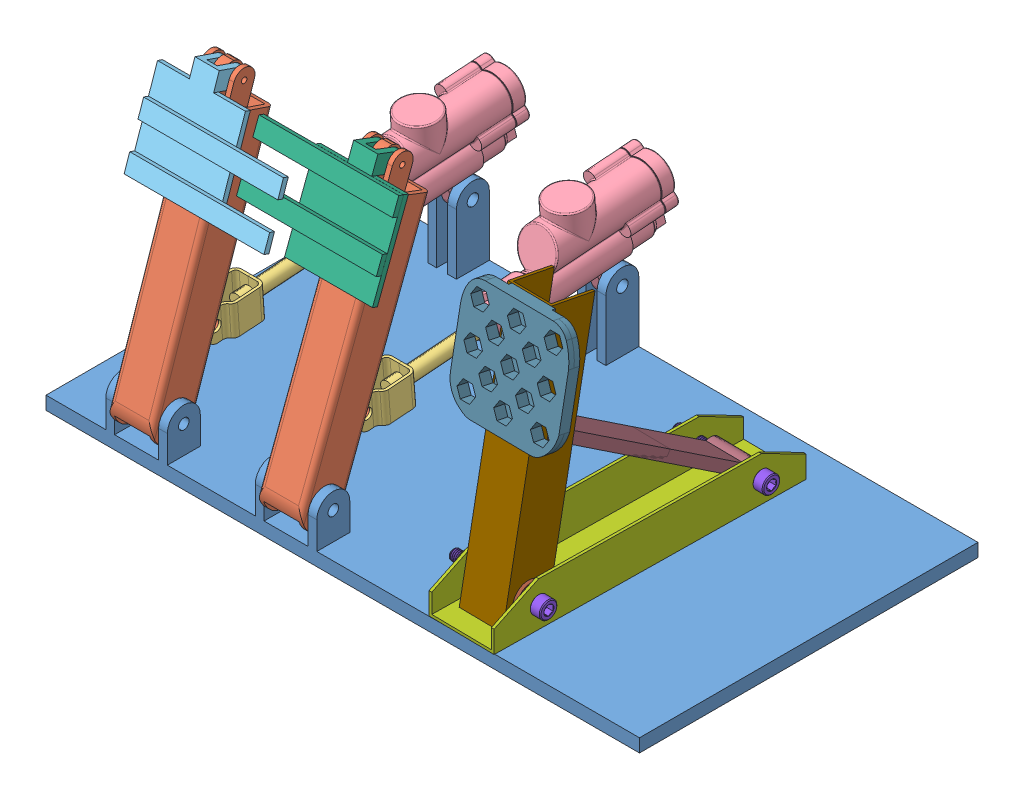
SolidWorks assembly full pedals, configuration Default. Lengths in mm.
Overall size (342.9 3166.43 584.97).
22 component instances, 14 part files, 14 mates.
Components (placement in the parent):
- pedal test base-1: pedal test base [Default] at (-68.8021 159.1968 370.0987) size (342.9 52.07 195.58)
- brake pedal arm-1: brake pedal arm [Default] at (-3.7758 166.587 352.6231) x (-1 0 0) z (0 -0.321031 -0.947069) size (25.4 171.45 40.13)
- brake pedal arm-2: brake pedal arm [Default] at (82.5842 166.3224 353.1832) x (-1 0 0) z (0 -0.3535 -0.935435) size (25.4 171.45 40.13)
- brake cylinder arm-1: brake cylinder arm [Default] at (69.8842 218.0458 207.3849) x (1 0 0) z (0 0.997042 0.076858) size (17.78 341.55 1584.44)
- brake cylinder arm-2: brake cylinder arm [Default] at (-16.4758 218.1643 208.2301) x (-1 0 0) z (0 -0.997624 -0.068895) size (17.78 341.55 1584.44)
- brake cylinder body-1: brake cylinder body [Default] at (69.8842 218.2186 205.144) x (-1 0 0) z (0 -0.997042 -0.076858) size (26.15 339.45 1611.72)
- brake cylinder body-2: brake cylinder body [Default] at (-16.4758 218.3865 205.0118) x (-1 0 0) z (0 -0.997624 -0.068895) size (26.15 339.45 1611.72)
- foot pedal-1: foot pedal [Default] at (8.9605 280.9267 349.0719) x (-1 0 0) z (0 -0.946173 0.323661) size (80.8 22.05 60.82)
- foot pedal 2-1: foot pedal 2 [Default] at (95.3205 280.4014 345.5905) x (-1 0 0) z (0 -0.935206 0.354104) size (80.86 22.05 60.82)
- Pedalassem-2: Pedalassem [Default] at (11.3745 77.4202 357.6928) x (0.013717 0 -0.999906) z (0.999906 0 0.013717) size (177.8 154.48 56.68)
  - PedalBase-1: PedalBase [Default] at (-10.3065 89.3967 179.2393) size (177.8 25.4 38.1)
  - 91292A144_18-8 Stainless Steel Socket Head Screw-3: 91292A144_18-8 Stainless Steel Socket Head Screw [91292A144] at (142.0935 102.0967 157.2393) size (10 10 56.68)
  - PedalShaft-2: PedalShaft [Default] at (50.2477 82.6782 173.3018) x (0.181898 0.983317 0) z (0 0 1) size (152.4 25.4 25.4)
  - 91292A144_18-8 Stainless Steel Socket Head Screw-4: 91292A144_18-8 Stainless Steel Socket Head Screw [91292A144] at (15.0935 102.0967 157.2393) x (0.996533 -0.083195 0) z (0 0 1) size (10 10 56.68)
  - 92871A198_18-8 Stainless Steel Unthreaded Spacer-2: 92871A198_18-8 Stainless Steel Unthreaded Spacer [92871A198] at (15.0935 102.0967 176.0643) size (13 13 3.17)
  - 92871A198_18-8 Stainless Steel Unthreaded Spacer-3: 92871A198_18-8 Stainless Steel Unthreaded Spacer [92871A198] at (15.0935 102.0967 144.3143) x (0.997287 0.073618 0) z (0 0 1) size (13 13 3.17)
  - Nylonbearing-1: Nylonbearing [Default] at (15.0935 102.0967 160.6018) x (0 0 -1) z (1 0 0) size (14.7 18 18)
  - Nylonbearing-2: Nylonbearing [Default] at (15.0935 102.0967 160.6018) x (0 0 1) z (-0.923728 -0.383049 0) size (14.7 18 18)
  - 90576A115_Medium-Strength Steel Nylon-Insert Locknut-1: 90576A115_Medium-Strength Steel Nylon-Insert Locknut [90576A115] at (15.0935 102.0967 138.1393) x (-0.897632 -0.440747 0) z (0 0 -1) size (10 11.55 6.37)
  - demo-1: demo [Default] at (73.5712 143.8787 149.4893) x (0.833738 -0.55216 0) z (0 0 1) size (86.2 12 22.23)
  - demo-2: demo [Default] at (97.4764 135.2435 149.4893) x (-0.833738 0.55216 0) z (0 0 1) size (86.2 12 22.23)
- g29 pedal-1: g29 pedal [Default] at (143.2116 257.1072 345.0029) x (0.999908 0.001237 0.013488) z (-0.013488 0.181898 0.983225) size (63.7 63.5 8.35)
Mates (geometry in assembly coordinates):
- Coincident1: coincident anti-aligned: circle of Part1-1; circle of brake pedal arm-1
- Coincident2: coincident anti-aligned: circle of Part1-1; circle of brake pedal arm-2
- Concentric5: concentric anti-aligned: cylinder of Part1-1 through (274.0979 201.7418 184.0437) axis (-1 0 0) radius 3.302; cylinder of brake cylinder body-2 through (-19.6508 201.7418 184.0437) axis (1 0 0) radius 3.2967
- Coincident3: coincident anti-aligned: plane of Part1-1 through (-13.3008 211.2668 370.0987) normal (-1 0 0); plane of brake cylinder body-2 through (-13.3008 201.7418 184.0437) normal (1 0 0)
- Concentric6: concentric anti-aligned: cylinder of Part1-1 through (274.0979 201.7418 184.0437) axis (-1 0 0) radius 3.302; cylinder of brake cylinder body-1 through (66.7092 201.7418 184.0437) axis (1 0 0) radius 3.2967
- Coincident4: coincident anti-aligned: plane of Part1-1 through (73.0592 211.2668 370.0987) normal (-1 0 0); plane of brake cylinder body-1 through (73.0592 201.7418 184.0437) normal (1 0 0)
- Concentric7: concentric anti-aligned: circle of brake cylinder arm-2; circle of brake cylinder body-2
- Concentric8: concentric anti-aligned: circle of brake cylinder arm-1; circle of brake cylinder body-1
- Coincident7: coincident anti-aligned: circle of brake pedal arm-2; circle of brake cylinder arm-1
- Coincident8: coincident anti-aligned: circle of brake pedal arm-1; circle of brake cylinder arm-2
- Coincident9: coincident aligned: circle of brake pedal arm-2; circle of foot pedal 2-1
- Coincident10: coincident aligned: circle of brake pedal arm-1; circle of foot pedal-1
- Coincident12: coincident anti-aligned: plane of Part1-1 through (-68.8021 166.8168 370.0987) normal (0 1 0); plane of Pedalassem-2/PedalBase-1 through (193.5913 166.8168 141.8784) normal (0 -1 0)
- Lock1: lock: unknown of Pedalassem-2/PedalShaft-2; unknown of g29 pedal-1
